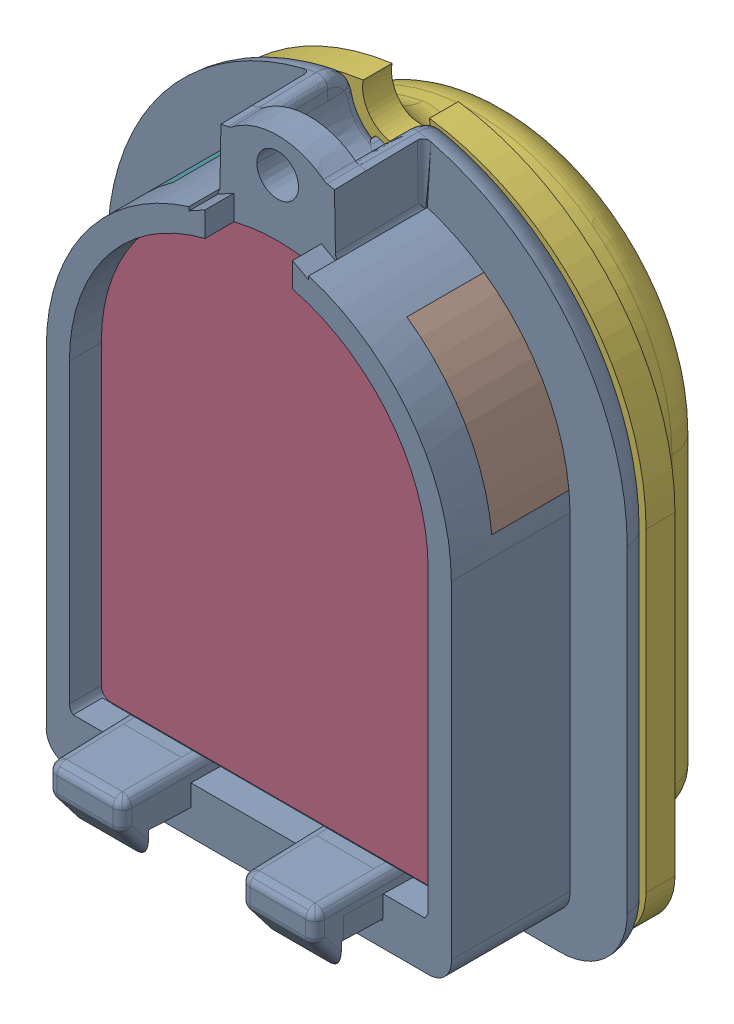
SolidWorks assembly BoardDesign, configuration 默认. Lengths in mm.
Overall size (26.95 34.26 17.16).
8 component instances, 7 part files, 21 mates.
Components (placement in the parent):
- BoardTip1-1: BoardTip1 [默认] at (-1.9035 7.7463 -5.5591) size (26.95 34.26 11.18)
- Boardlensnew-1: Boardlensnew [默认] at (-1.9035 7.7463 -5.5591) size (18.6 25.2 6)
- BoardSkin0.2-1: BoardSkin0.2 [默认] at (-1.9035 7.4963 -5.5591) x (-1 0 0) z (0 0 -1) size (23.9 30.06 5.2)
- Skin1-2: Skin1 [默认] at (-1.9035 7.4963 -5.5591) x (-1 0 0) z (0 0 -1) size (25.9 32.24 6)
- Boardsidelens1-1: Boardsidelens1 [默认] at (-1.9035 7.7463 -6.2091) size (6.4 7.71 4)
- Boardsidelens1-2: Boardsidelens1 [默认] at (-1.9035 7.7463 2.0909) x (-1 0 0) z (0 0 -1) size (6.4 7.71 4)
- Boardbottomlens-1: Boardbottomlens [默认] at (-5.9035 -10.5037 0.4409) x (1 0 0) z (0 1 0) size (8 4.5 2.35)
- BoardChessboardDigit-1: BoardChessboardDigit [默认] at (-15.1693 -0.6894 -10.3591) x (0 1 0) z (0 0 -1) size (22.5 14.3 0.4)
Mates (geometry in assembly coordinates):
- 同心1: concentric aligned: cylinder of BoardTip1-1 through (-1.9035 7.7463 51.2878) axis (0 0 -1) radius 9.3; cylinder of lensnew-1 through (-1.9035 7.7463 0.4409) axis (0 0 -1) radius 9.3
- 重合1: coincident anti-aligned: plane of BoardTip1-1 through (-1.9035 -8.1537 51.2878) normal (0 1 0); plane of lensnew-1 through (-11.2035 -8.1537 0.4409) normal (0 -1 0)
- 重合2: coincident aligned: plane of BoardTip1-1 through (-1.964 4.3089 -5.5591) normal (0 0 -1); plane of lensnew-1 through (-1.9035 7.7463 -5.5591) normal (0 0 -1)
- 重合3: coincident anti-aligned: plane of lensnew-1 through (-1.9035 7.7463 -5.5591) normal (0 0 -1); plane of Skin0.2-1 through (-1.9035 7.4963 -5.5591) normal (0 0 1)
- 同心2: concentric aligned: cone of BoardTip1-1 through (-1.9035 19.9963 -1.0591) axis (0 0 1); cylinder of Skin0.2-1 through (-1.9035 19.9963 -6.3091) axis (0 0 1) radius 2.75
- 宽度1: width aligned: plane of Skin0.2-1 through (-13.8535 7.4963 -5.5591) normal (-1 0 0); plane of BoardTip1-1 through (10.0465 7.4963 -5.5591) normal (1 0 0); plane of Skin0.2-1 through (-12.4035 7.7463 2.0909) normal (-1 0 0); plane of BoardTip1-1 through (8.5965 7.7463 2.0909) normal (1 0 0)
- 重合4: coincident anti-aligned: plane of Skin0.2-1 through (-1.9035 7.4963 -10.7591) normal (0 0 -1); plane of Skin1-2 through (-1.9035 7.4963 -10.7591) normal (0 0 1)
- 重合6: coincident anti-aligned: plane of BoardTip1-1 through (-16.7251 9.2061 -4.0591) normal (0.104528 0.994522 0); plane of sidelens1-1 through (8.4147 6.5638 -0.0591) normal (-0.104528 -0.994522 0)
- 重合7: coincident anti-aligned: plane of BoardTip1-1 through (-1.9035 7.7463 -4.0591) normal (0 0 1); plane of sidelens1-1 through (8.4147 6.5638 -4.0591) normal (0 0 -1)
- 同心3: concentric aligned: cylinder of BoardTip1-1 through (-1.9035 7.7463 2.0909) axis (0 0 -1) radius 10.5; cylinder of sidelens1-1 through (-1.9035 7.7463 -0.0591) axis (0 0 -1) radius 10.5
- 同心4: concentric anti-aligned: cylinder of BoardTip1-1 through (-1.9035 7.7463 2.0909) axis (0 0 -1) radius 10.5; cylinder of sidelens1-2 through (-1.9035 7.7463 -4.0591) axis (0 0 1) radius 10.5
- 重合8: coincident anti-aligned: plane of BoardTip1-1 through (12.0819 17.1622 -0.0591) normal (0.104528 -0.994522 0); plane of sidelens1-2 through (-13.0579 14.5199 -4.0591) normal (-0.104528 0.994522 0)
- 重合9: coincident anti-aligned: plane of BoardTip1-1 through (-1.9035 7.7463 -4.0591) normal (0 0 1); plane of sidelens1-2 through (-1.9035 7.7463 -4.0591) normal (0 0 -1)
- 重合10: coincident anti-aligned: plane of lensnew-1 through (-11.2035 -8.1537 0.4409) normal (0 -1 0); plane of bottomlens-1 through (-5.9035 -8.1537 0.4409) normal (0 1 0)
- 重合11: coincident anti-aligned: plane of BoardTip1-1 through (-5.9035 -18.1537 0.4409) normal (0 0 -1); plane of bottomlens-1 through (-5.9035 -8.1537 0.4409) normal (0 0 1)
- 重合12: coincident anti-aligned: plane of BoardTip1-1 through (2.0965 -18.1537 0.4409) normal (-1 0 0); plane of bottomlens-1 through (2.0965 -8.1537 0.4409) normal (1 0 0)
- 宽度4: width aligned: plane of BoardTip1-1 through (8.5965 7.7463 2.0909) normal (1 0 0); plane of BoardTip1-1 through (-12.4035 7.7463 2.0909) normal (-1 0 0); plane of ChessboardDigit-1 through (5.2465 4.9053 -10.7591) normal (1 0 0); plane of ChessboardDigit-1 through (-9.0535 9.0053 -10.7591) normal (-1 0 0)
- 距离2: distance = 2 mm aligned: plane of Skin1-2 through (7.3875 -9.3947 -5.5591) normal (0 -1 0); plane of ChessboardDigit-1 through (-2.9535 -7.3947 -10.7591) normal (0 -1 0)
- 重合14: coincident aligned: plane of Skin0.2-1 through (-1.9035 7.4963 -10.7591) normal (0 0 -1); plane of ChessboardDigit-1 through (-11.0693 7.5106 -10.7591) normal (0 0 -1)
- 宽度5: width aligned: plane of Skin1-2 through (-14.8535 7.4963 -5.5591) normal (-1 0 0); plane of Skin1-2 through (11.0465 7.4963 -5.5591) normal (1 0 0); plane of BoardSkin0.2-1 through (-13.8535 7.4963 -5.5591) normal (-1 0 0); plane of BoardSkin0.2-1 through (10.0465 7.4963 -5.5591) normal (1 0 0)
- 同心5: concentric aligned: cylinder of BoardSkin0.2-1 through (-1.9035 19.9963 -6.3091) axis (0 0 1) radius 2.75; cylinder of Skin1-2 through (-1.9035 19.9963 -6.3091) axis (0 0 1) radius 1.75
